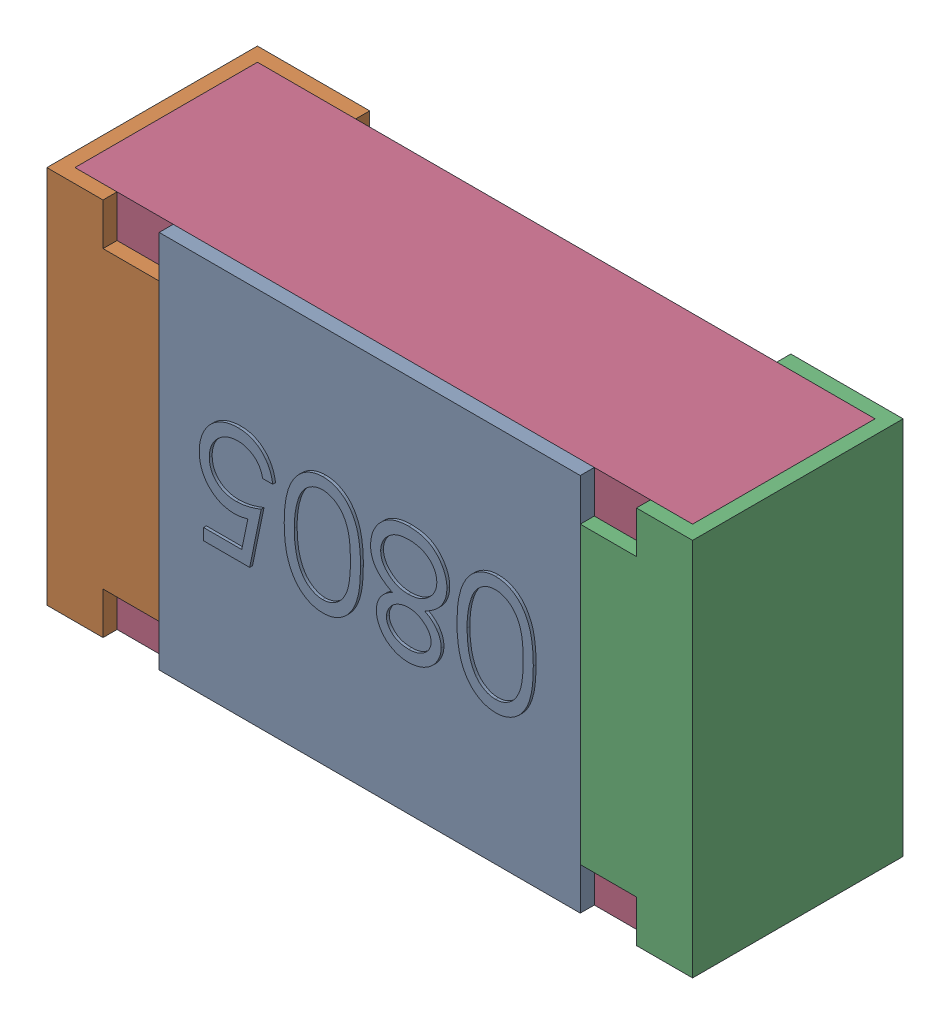
SolidWorks assembly R37, configuration Standard. Lengths in mm.
Overall size (2.3 1.35 0.76).
5 component instances, 4 part files, 0 mates.
Components (placement in the parent):
- R37-subassembly-1-1: R37-subassembly-1 [Standard] at (9.2999 6.7999 0) x (-1 0 0) z (0 1 0) size (2.3 0.76 1.35)
  - User Library-RES_2013-0805-1: User Library-RES_2013-0805 [Standard] at origin size (1.5 0.06 1.35)
  - User Library-RES_2013-0805-1-1: User Library-RES_2013-0805-1 [Standard] at origin size (0.4 0.75 1.35)
  - User Library-RES_2013-0805-2-1: User Library-RES_2013-0805-2 [Standard] at origin size (0.4 0.75 1.35)
  - User Library-RES_2013-0805-3-1: User Library-RES_2013-0805-3 [Standard] at origin size (2.2 0.65 1.35)
